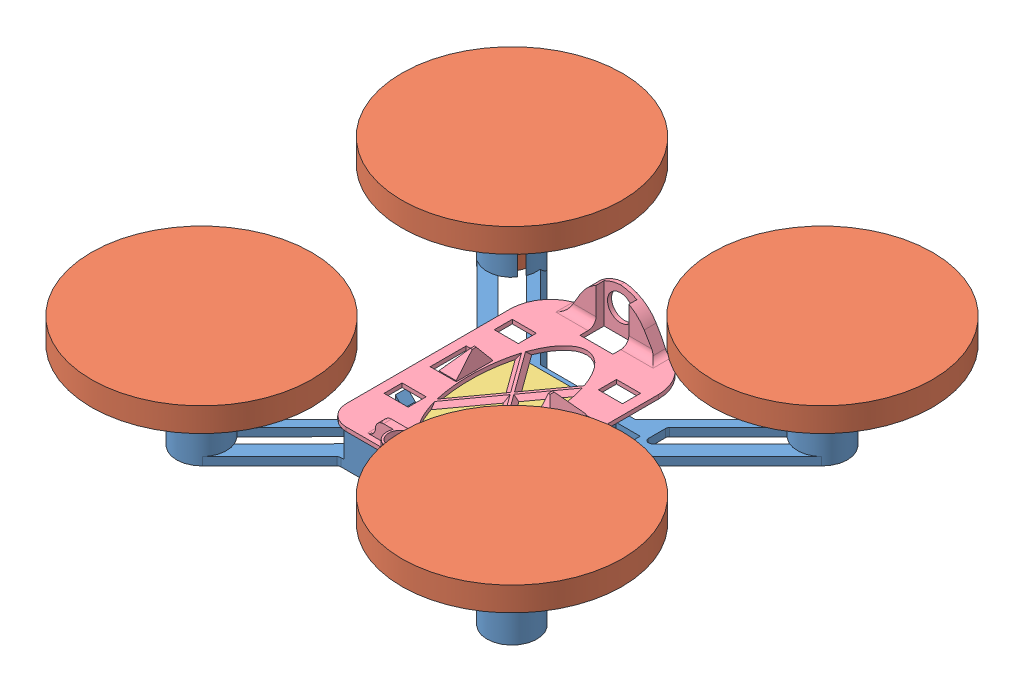
SolidWorks assembly Montagem1, configuration Valor predeterminado. Lengths in mm.
Overall size (140.35 28 140.35).
7 component instances, 4 part files, 11 mates.
Components (placement in the parent):
- Base-1: Base [Valor predeterminado] at (-60.5373 -9.1214 0) size (90 13 90)
- Motor + Prop-1: Motor + Prop [Valor predeterminado] at (-99.2873 -7.1214 38.75) size (55 26 55)
- Motor + Prop-2: Motor + Prop [Valor predeterminado] at (-21.7873 -7.1214 38.75) size (55 26 55)
- Motor + Prop-3: Motor + Prop [Valor predeterminado] at (-99.2873 -7.1214 -38.75) x (0.937417 0 -0.348208) z (0.348208 0 0.937417) size (55 26 55)
- Motor + Prop-4: Motor + Prop [Valor predeterminado] at (-21.7873 -7.1214 -38.75) size (55 26 55)
- Eletronica-2: Eletronica [Valor predeterminado] at (-60.5373 0.8786 7.5) x (0 0 -1) z (0 -1 0) size (35 20 8) (hidden)
- Top D-1: Top D [Valor predeterminado] at (-60.5036 1.1464 4.9592) x (0 0 -1) z (1 0 0) size (59.09 10.98 37)
Mates (geometry in assembly coordinates):
- Coincidente1: coincident aligned: plane of Base-1 through (-60.5373 -7.1214 0) normal (0 1 0); circle of Motor + Prop-1
- Coincidente2: coincident anti-aligned: plane of Base-1 through (-60.5373 -7.1214 0) normal (0 1 0); plane of Motor + Prop-1 through (-99.2873 -7.1214 38.75) normal (0 -1 0)
- Concêntrico1: concentric aligned: cylinder of Base-1 through (-99.2873 3.8786 38.75) axis (0 -1 0) radius 4.625; cylinder of Motor + Prop-1 through (-99.2873 12.8786 38.75) axis (0 -1 0) radius 4.25
- Coincidente5: coincident aligned: plane of Base-1 through (-60.5373 -7.1214 0) normal (0 1 0); circle of Motor + Prop-3
- Concêntrico2: concentric aligned: cylinder of Base-1 through (-99.2873 3.8786 -38.75) axis (0 -1 0) radius 4.625; cylinder of Motor + Prop-3 through (-99.2873 12.8786 -38.75) axis (0 -1 0) radius 4.25
- Coincidente6: coincident aligned: plane of Base-1 through (-60.5373 -7.1214 0) normal (0 1 0); circle of Motor + Prop-4
- Concêntrico3: concentric aligned: cylinder of Base-1 through (-21.7873 3.8786 -38.75) axis (0 -1 0) radius 4.625; cylinder of Motor + Prop-4 through (-21.7873 12.8786 -38.75) axis (0 -1 0) radius 4.25
- Coincidente66: coincident anti-aligned: plane of Base-1 through (-60.5373 -7.1214 0) normal (0 1 0); plane of Eletronica-2 through (-60.5373 -7.1214 7.5) normal (0 -1 0)
- Coincidente68: coincident anti-aligned: plane of Base-1 through (-76.5373 0.8786 25) normal (0 0 -1); plane of Eletronica-2 through (-50.5373 -7.1214 25) normal (0 0 1)
- Paralelo2: parallel aligned: line of Base-1 through (-76.5373 -7.1214 -4.5) axis (0 0 1); line of Top D-1 through (-76.5036 2.1464 -4.5408) axis (0 0 1)
- Paralelo1: parallel aligned: line of Base-1 through (-44.5373 -7.1214 -16) axis (-1 0 0); line of Top D-1 through (-44.5036 2.1464 -16.0408) axis (-1 0 0)
